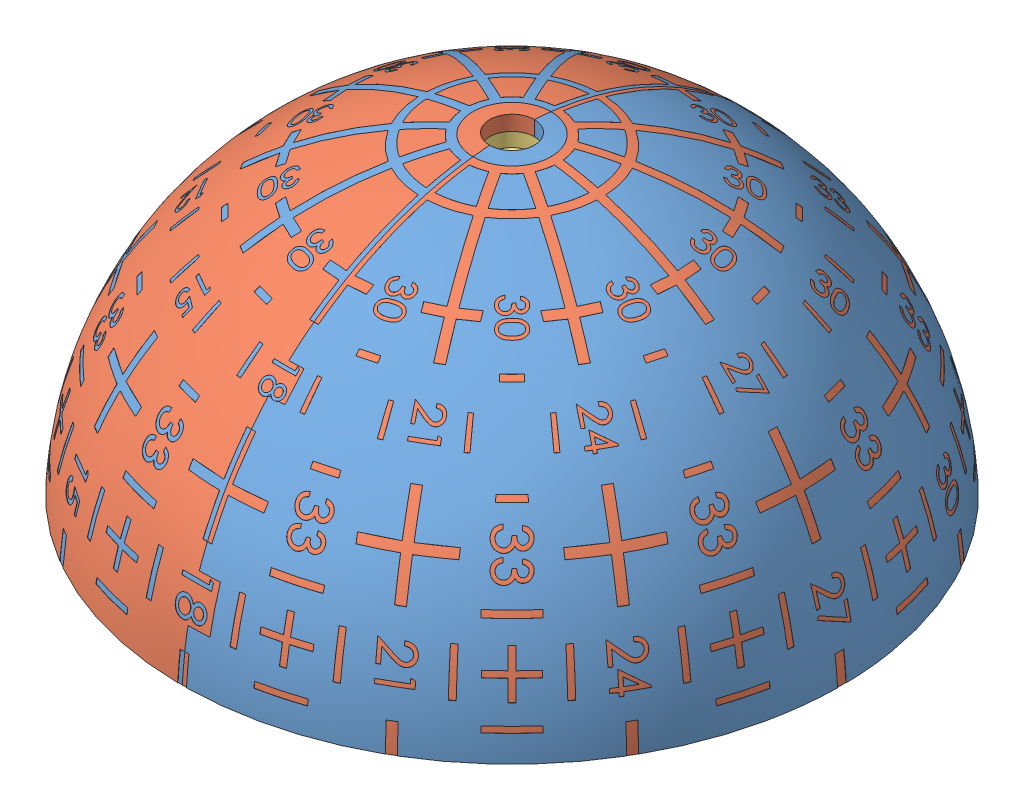
SolidWorks assembly TopPrint, configuration Default. Lengths in mm.
Overall size (88.79 42.35 88.79).
3 component instances, 3 part files, 4 mates.
Components (placement in the parent):
- Black-1: Black [Default] at origin size (88.75 42.35 88.79)
- White-1: White [Default] at origin size (88.75 42.35 88.79)
- Part1^TopPrint-1: Part1^TopPrint [Default] x (1 0 0) z (0 1 0) size (15.57 15.57 3.97)
Mates (geometry in assembly coordinates):
- InPlace1: in place: plane of Part1^TopPrint-1 through (0 0 0) normal (0 1 0); moOrthogonalPlaneRef_w of Part1^TopPrint-1 through (0 0 0) normal (0 0 -1); plane of Part1^TopPrint-1 through (0 0 0) normal (1 0 0); unknown of Part1^TopPrint-1
- Coincident1: coincident: plane of Part1^TopPrint-1; plane of assembly
- Coincident2: coincident: plane of Part1^TopPrint-1 through (0 0 0) normal (0 0 -1); moOrthogonalPlaneRef_w of assembly
- Coincident3: coincident: plane of Part1^TopPrint-1 through (0 0 0) normal (1 0 0); moOrthogonalPlaneRef_w of assembly
